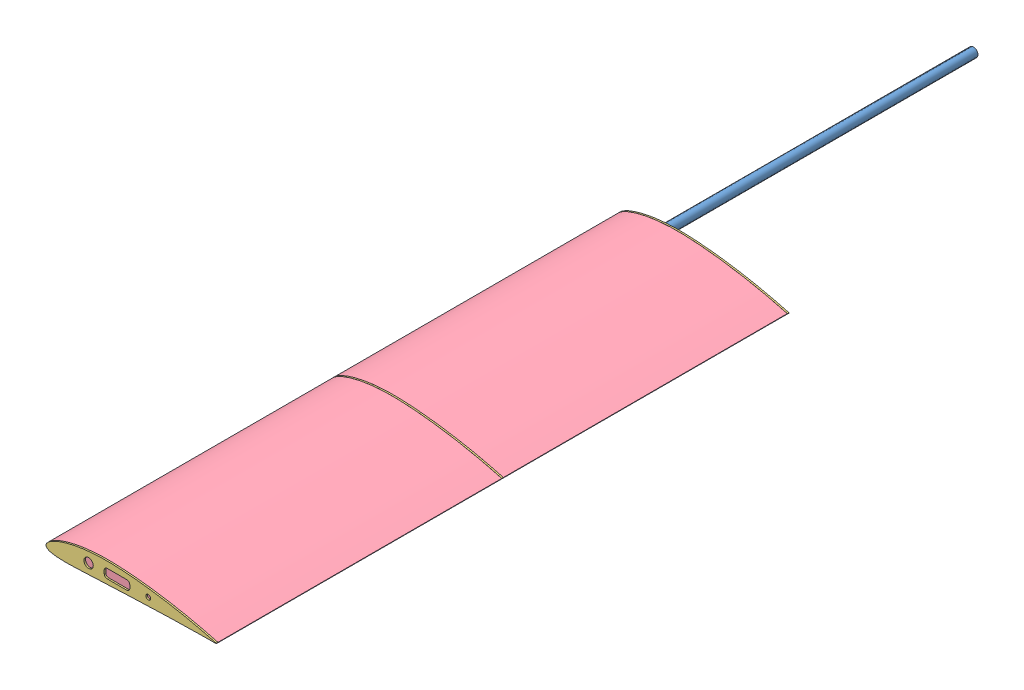
SolidWorks assembly WingLeft, configuration Default. Lengths in mm.
Overall size (300.16 38.54 1558.4).
7 component instances, 4 part files, 16 mates.
Components (placement in the parent):
- CarbonTubeD16mmL1m-1: CarbonTubeD16mmL1m [Default] at (479.5115 365.1997 426.5267) size (16 16 1000)
- CarbonTubeD8mmL0.5m-1: CarbonTubeD8mmL0.5m [Default] at (584.5654 365.5466 726.5267) x (0.766068 -0.642759 0) z (0 0 1) size (8 8 500)
- polywoodRib300mm-1: polywoodRib300mm [Default] at (404.4705 354.8841 477.9267) size (300.16 38.54 2.8)
- XPSWingPart500mm-1: XPSWingPart500mm [Default] at (404.4705 354.8841 729.3267) size (300.16 38.54 500)
- polywoodRib300mm-2: polywoodRib300mm [Default] at (404.4705 354.8841 980.7267) size (300.16 38.54 2.8)
- XPSWingPart500mm-2: XPSWingPart500mm [Default] at (404.4705 354.8841 1232.1267) size (300.16 38.54 500)
- polywoodRib300mm-3: polywoodRib300mm [Default] at (404.4705 354.8841 1483.5267) size (300.16 38.54 2.8)
Mates (geometry in assembly coordinates):
- Совпадение1: coincident anti-aligned: plane of polywoodRib300mm-1 through (552.9013 350.6045 479.3267) normal (0 0 1); plane of XPSWingPart500mm-1 through (552.9013 350.6045 479.3267) normal (0 0 -1)
- Совпадение2: coincident aligned: circle of polywoodRib300mm-1; circle of XPSWingPart500mm-1
- Совпадение3: coincident aligned: line of polywoodRib300mm-1 through (404.5281 355.6298 479.3267) axis (-0.076973 -0.997033 0); line of XPSWingPart500mm-1 through (404.5281 355.6298 479.3267) axis (-0.076973 -0.997033 0)
- Совпадение4: coincident anti-aligned: plane of XPSWingPart500mm-1 through (552.9013 350.6045 979.3267) normal (0 0 1); plane of polywoodRib300mm-2 through (552.9013 350.6045 979.3267) normal (0 0 -1)
- Совпадение5: coincident aligned: circle of XPSWingPart500mm-1; circle of polywoodRib300mm-2
- Совпадение6: coincident aligned: line of XPSWingPart500mm-1 through (404.5281 355.6298 979.3267) axis (-0.076973 -0.997033 0); line of polywoodRib300mm-2 through (404.5281 355.6298 979.3267) axis (-0.076973 -0.997033 0)
- Совпадение7: coincident anti-aligned: plane of polywoodRib300mm-2 through (552.9013 350.6045 982.1267) normal (0 0 1); plane of XPSWingPart500mm-2 through (552.9013 350.6045 982.1267) normal (0 0 -1)
- Совпадение8: coincident aligned: circle of polywoodRib300mm-2; circle of XPSWingPart500mm-2
- Совпадение9: coincident aligned: line of polywoodRib300mm-2 through (404.5281 355.6298 982.1267) axis (-0.076973 -0.997033 0); line of XPSWingPart500mm-2 through (404.5281 355.6298 982.1267) axis (-0.076973 -0.997033 0)
- Совпадение10: coincident anti-aligned: plane of XPSWingPart500mm-2 through (552.9013 350.6045 1482.1267) normal (0 0 1); plane of polywoodRib300mm-3 through (552.9013 350.6045 1482.1267) normal (0 0 -1)
- Совпадение11: coincident aligned: circle of XPSWingPart500mm-2; circle of polywoodRib300mm-3
- Совпадение12: coincident aligned: line of XPSWingPart500mm-2 through (404.5281 355.6298 1482.1267) axis (-0.076973 -0.997033 0); line of polywoodRib300mm-3 through (404.5281 355.6298 1482.1267) axis (-0.076973 -0.997033 0)
- Концентричный1: concentric aligned: cylinder of CarbonTubeD8mmL0.5m-1 through (584.5654 365.5466 976.5267) axis (0 0 -1) radius 4; cylinder of polywoodRib300mm-1 through (584.5654 365.5466 479.3267) axis (0 0 -1) radius 4.25
- Совпадение13: coincident aligned: plane of CarbonTubeD8mmL0.5m-1 through (584.5654 365.5466 476.5267) normal (0 0 -1); plane of polywoodRib300mm-1 through (552.9013 350.6045 476.5267) normal (0 0 -1)
- Концентричный2: concentric aligned: cylinder of CarbonTubeD16mmL1m-1 through (479.5115 365.1997 926.5267) axis (0 0 -1) radius 8; cylinder of polywoodRib300mm-1 through (479.5115 365.1997 479.3267) axis (0 0 -1) radius 8.25
- Расстояние1: distance = 550 mm aligned: plane of polywoodRib300mm-1 through (552.9013 350.6045 476.5267) normal (0 0 -1); plane of CarbonTubeD16mmL1m-1 through (479.5115 365.1997 -73.4733) normal (0 0 -1)
